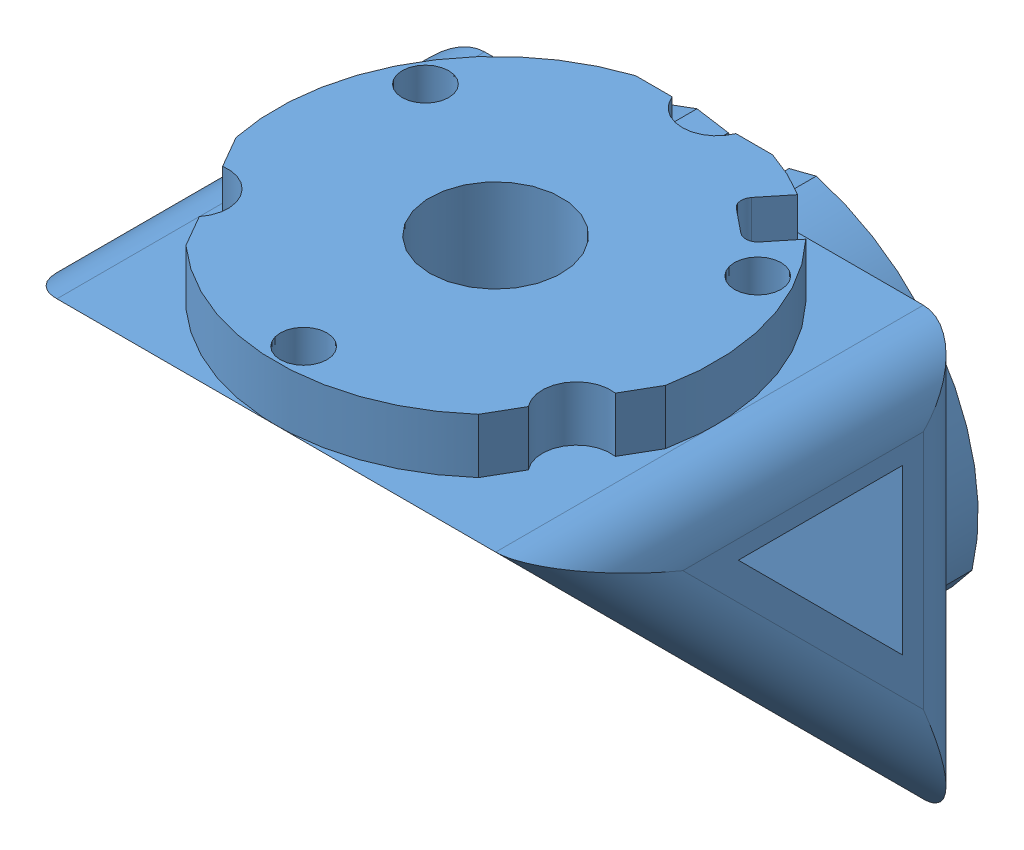
SolidWorks assembly interfaccia_doppio_gripper_costruzione, configuration Default. Lengths in mm.
Overall size (100 88 88).
2 component instances, 2 part files, 3 mates.
Components (placement in the parent):
- interfaccia_doppio_gripper-1: interfaccia_doppio_gripper [Default] at (-2.8348 -3.3437 1.1789) size (100 88 88)
- IRB4600_20kg-250_LINK6_CAD_rev04.step-1: IRB4600_20kg-250_LINK6_CAD_rev04.step [Default] at (56.7022 -2248.402 -130.3091) x (0 0.707107 -0.707107) z (0 0.707107 0.707107)
Mates (geometry in assembly coordinates):
- Distanza1: distance = 10 mm: plane of IRB4600_20kg-250_LINK6_CAD_rev04.step-1 through (40.9522 53.5841 63.7917) normal (0 0.707107 -0.707107); plane of interfaccia_doppio_gripper-1 through (6.7022 99.2194 95.2847) normal (0 -0.707107 0.707107)
- Perpendicolare1: perpendicular: plane of interfaccia_doppio_gripper-1 through (56.7022 -3.3437 1.1789) normal (-1 0 0); plane of IRB4600_20kg-250_LINK6_CAD_rev04.step-1 through (56.7022 29.5425 87.8333) normal (0 -0.707107 0.707107)
- Coincidente6: coincident aligned: plane of interfaccia_doppio_gripper-1 through (56.7022 -3.3437 1.1789) normal (-1 0 0); plane of IRB4600_20kg-250_LINK6_CAD_rev04.step-1 through (56.7022 -2248.402 -130.3091) normal (-1 0 0)
